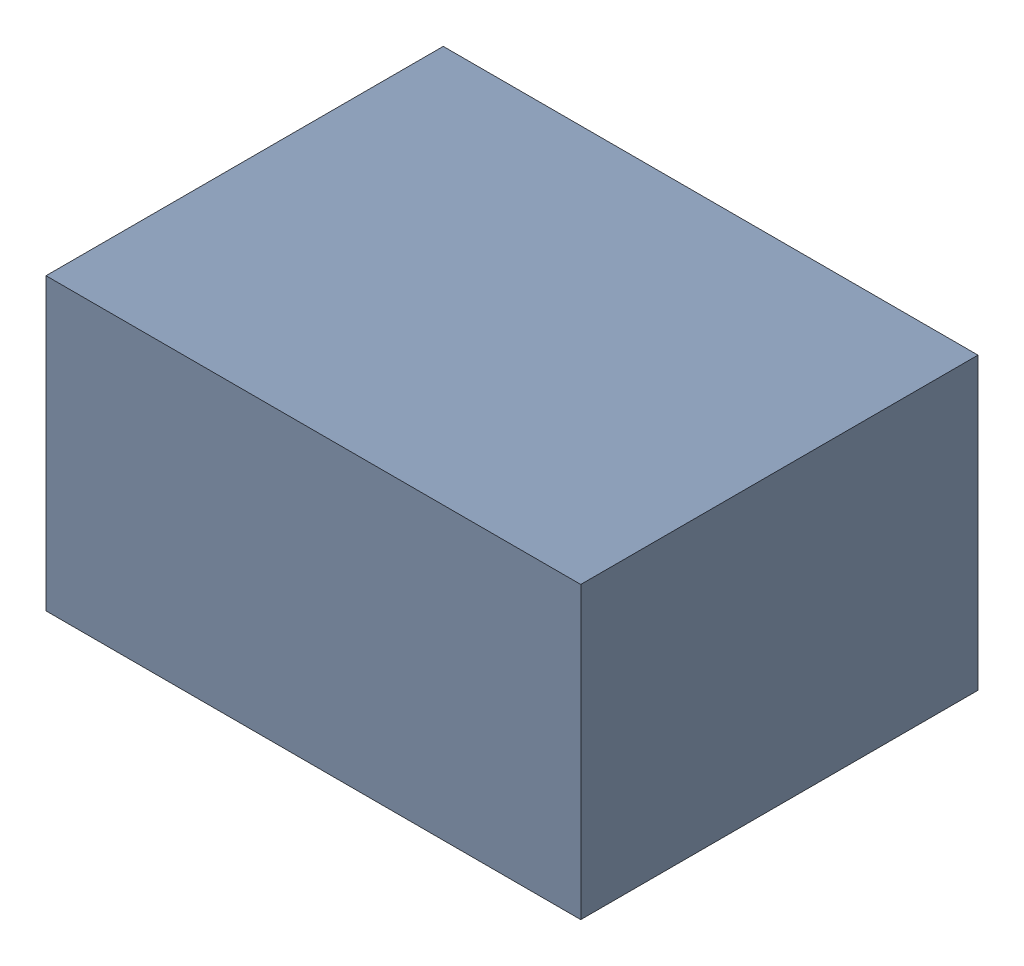
SolidWorks assembly C4, configuration Default. Lengths in mm.
Overall size (1.75 0.95 1.3).
2 component instances, 1 part files, 0 mates.
Components (placement in the parent):
- 580487056-1: 580487056 [Default] at (226.568 110.871 0) size (1.75 0.95 1.3)
  - Extruded_7-1: Extruded_7 [Default] at origin size (1.75 0.95 1.3)
